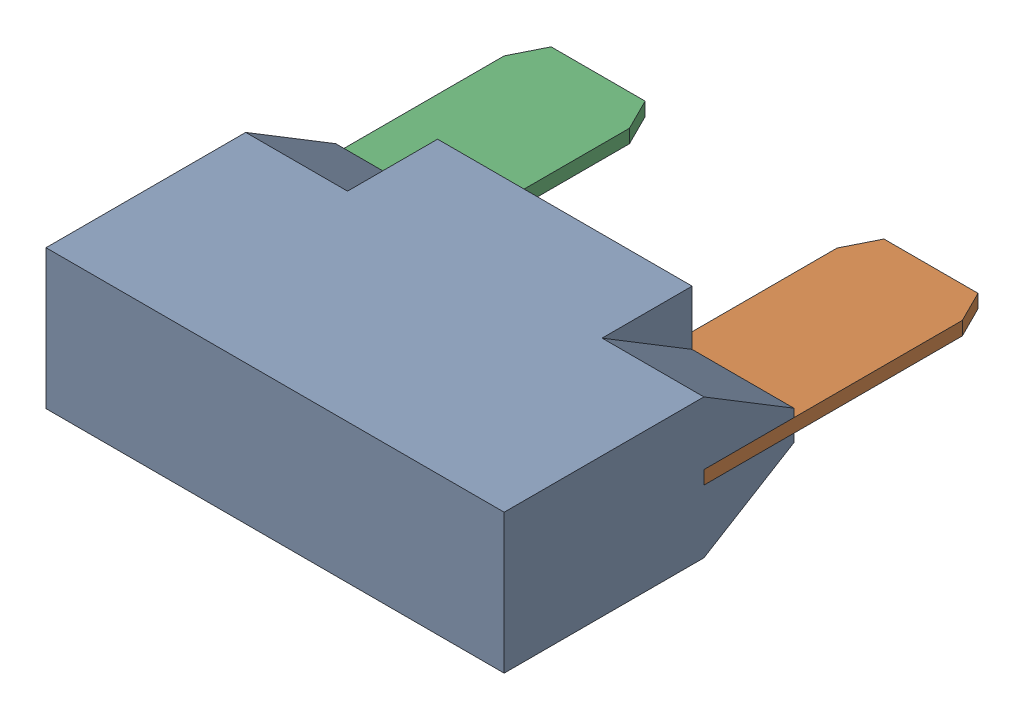
SolidWorks assembly Maxi Fuse, configuration Default. Lengths in mm.
Overall size (29.25 8.9 31.25).
3 component instances, 2 part files, 0 mates.
Components (placement in the parent):
- Maxi Fuse - Body-1: Maxi Fuse - Body [Default] at origin size (29.25 8.9 18.5)
- Maxi Fuse - Terminal-1: Maxi Fuse - Terminal [Default] at (10.625 0 -12.75) x (-1 0 0) z (0 1 0) size (8 18.5 0.86)
- Maxi Fuse - Terminal-2: Maxi Fuse - Terminal [Default] at (-10.625 0 -12.75) x (1 0 0) z (0 -1 0) size (8 18.5 0.86)
